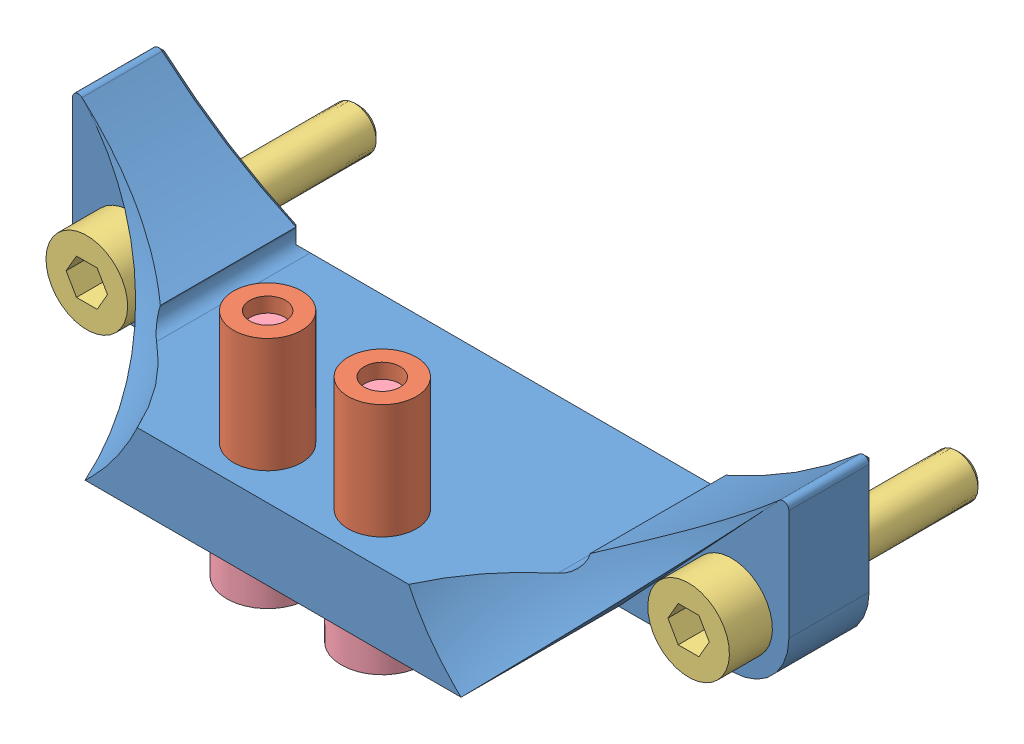
SolidWorks assembly bed-mount-assy, configuration Default. Lengths in mm.
Overall size (50 16 27.21).
7 component instances, 4 part files, 12 mates.
Components (placement in the parent):
- 1245-1: 1245 [Default] at origin size (50 13 17)
- M3x8-spacer-1: M3x8-spacer [Default] at (4 -4.5 13.38) x (0 0 1) z (0 1 0) size (4.76 4.76 8)
- M3x8-spacer-2: M3x8-spacer [Default] at (-4 -4.5 13.38) x (0 0 1) z (0 1 0) size (4.76 4.76 8)
- 242-1: 242 [Default] at (-21 -5.5 6) x (-0.866025 -0.5 0) z (0 0 1) size (5.7 5.7 19)
- 242-2: 242 [Default] at (21 -5.5 6) x (-0.866025 -0.5 0) z (0 0 1) size (5.7 5.7 19)
- 257-1: 257 [Default] at (-4 -9.5 13.38) x (0.45003 0 -0.893014) z (0 -1 0) size (5.7 5.7 15)
- 257-2: 257 [Default] at (4 -9.5 13.38) x (-0.999053 0 -0.043516) z (0 -1 0) size (5.7 5.7 15)
Mates (geometry in assembly coordinates):
- Coincident106: coincident anti-aligned: plane of 1245-1 through (-15 -4.5 17) normal (0 1 0); plane of M3x8-spacer-1 through (4 -4.5 13.38) normal (0 -1 0)
- Concentric135: concentric aligned: cylinder of 1245-1 through (4 2.6163 13.38) axis (0 -1 0) radius 1.65; cylinder of M3x8-spacer-1 through (4 3.5 13.38) axis (0 -1 0) radius 1.25
- Coincident107: coincident anti-aligned: plane of 1245-1 through (-15 -4.5 17) normal (0 1 0); plane of M3x8-spacer-2 through (-4 -4.5 13.38) normal (0 -1 0)
- Concentric136: concentric aligned: cylinder of 1245-1 through (-4 2.6163 13.38) axis (0 -1 0) radius 1.65; cylinder of M3x8-spacer-2 through (-4 3.5 13.38) axis (0 -1 0) radius 1.25
- Coincident156: coincident anti-aligned: plane of 1245-1 through (-24.6 2.2163 6) normal (0 0 1); plane of 242-1 through (-21 -5.5 6) normal (0 0 -1)
- Concentric194: concentric anti-aligned: cylinder of 1245-1 through (-21 -5.5 17) axis (0 0 -1) radius 1.725; cylinder of 242-1 through (-21 -5.5 -10) axis (0 0 1) radius 1.5
- Coincident157: coincident anti-aligned: plane of 1245-1 through (-24.6 2.2163 6) normal (0 0 1); plane of 242-2 through (21 -5.5 6) normal (0 0 -1)
- Concentric195: concentric anti-aligned: cylinder of 1245-1 through (21 -5.5 17) axis (0 0 -1) radius 1.725; cylinder of 242-2 through (21 -5.5 -10) axis (0 0 1) radius 1.5
- Concentric246: concentric aligned: cylinder of 1245-1 through (-4 2.6163 13.38) axis (0 -1 0) radius 1.65; cylinder of 257-1 through (-4 2.5 13.38) axis (0 -1 0) radius 1.5
- Concentric247: concentric aligned: cylinder of 1245-1 through (4 2.6163 13.38) axis (0 -1 0) radius 1.65; cylinder of 257-2 through (4 2.5 13.38) axis (0 -1 0) radius 1.5
- Coincident196: coincident anti-aligned: plane of 1245-1 through (-21 -9.5 17) normal (0 -1 0); plane of 257-1 through (-4 -9.5 13.38) normal (0 1 0)
- Coincident197: coincident anti-aligned: plane of 1245-1 through (-21 -9.5 17) normal (0 -1 0); plane of 257-2 through (4 -9.5 13.38) normal (0 1 0)
